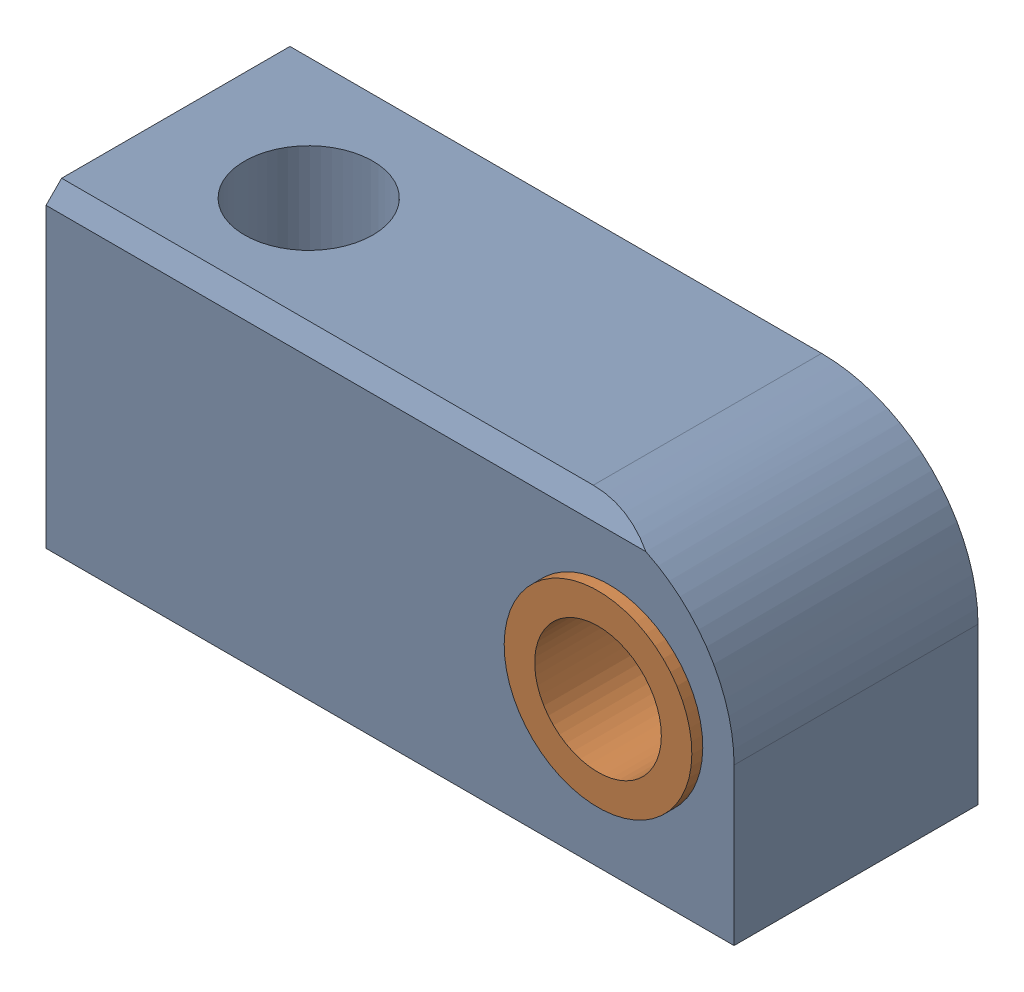
SolidWorks assembly Sabot et bague inox, configuration Défaut. Lengths in mm.
Overall size (22.09 10 8.5).
2 component instances, 2 part files, 2 mates.
Components (placement in the parent):
- Sabot-1: Sabot [Défaut] at (8.6997 -4.2299 0) size (22 10 7.8)
- Bague Inox-1: Bague Inox [Défaut] at (4.6997 0.7701 0) x (-0.491823 0.870695 0) z (0 0 1) size (6 6 8.5)
Mates (geometry in assembly coordinates):
- Coïncidente1: coincident aligned: plane of Sabot-1; plane of Bague Inox-1
- Coaxiale1: concentric aligned: cylinder of Sabot-1 through (4.6997 0.7701 3.9) axis (0 0 -1) radius 2.99; cylinder of Bague Inox-1 through (4.6997 0.7701 4.25) axis (0 0 -1) radius 3
